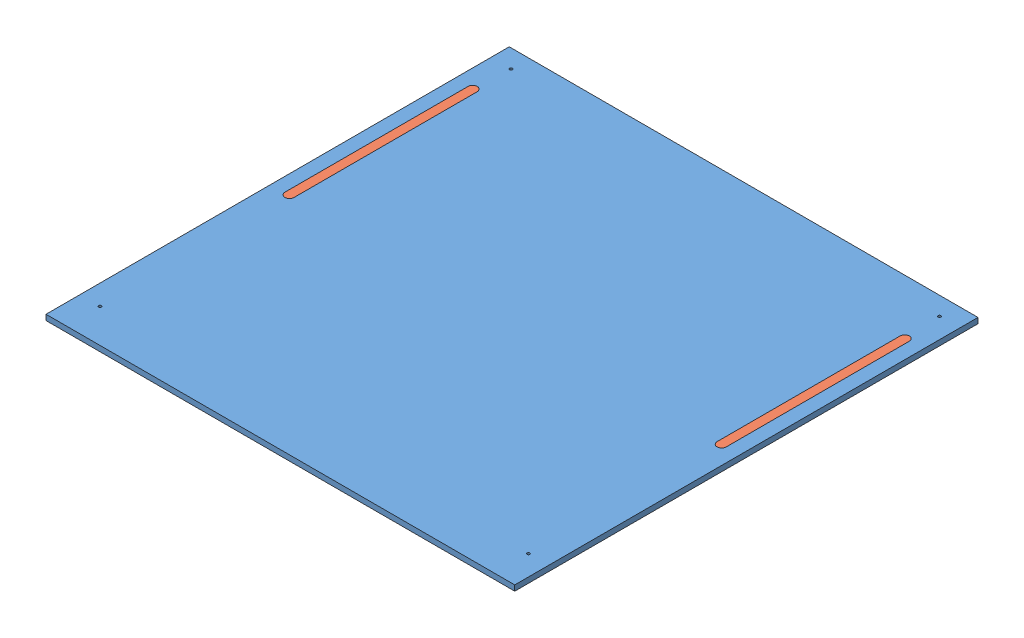
SolidWorks assembly top_board_light_stripe_assem, configuration Default. Lengths in mm.
Overall size (512 6 506).
3 component instances, 2 part files, 5 mates.
Components (placement in the parent):
- top_board_light_stripe-1: top_board_light_stripe [Default] at (107.7343 336.6542 389.8099) size (512 6 506)
- light_reflector-1: light_reflector [Default] at (121.7343 342.6542 449.8099) x (0 0 1) z (1 0 0) size (210 6 10)
- light_reflector-3: light_reflector [Default] at (593.7343 342.6542 449.8099) x (0 0 1) z (1 0 0) size (210 6 10)
Mates (geometry in assembly coordinates):
- Concentric1: concentric anti-aligned: cylinder of top_board_light_stripe-1 through (121.7343 342.6542 449.8099) axis (0 -1 0) radius 5; cylinder of light_reflector-1 through (121.7343 336.6542 449.8099) axis (0 1 0) radius 5
- Concentric2: concentric aligned: cylinder of top_board_light_stripe-1 through (121.7343 342.6542 649.8099) axis (0 -1 0) radius 5; circle of light_reflector-1
- Coincident2: coincident anti-aligned: line of top_board_light_stripe-1 through (116.7343 342.6542 449.8099) axis (0 0 1); line of light_reflector-1 through (116.7343 342.6542 649.8099) axis (0 0 -1)
- Concentric3: concentric: cylinder of top_board_light_stripe-1 through (593.7343 342.6542 649.8099) axis (0 -1 0) radius 5; cylinder of light_reflector-3 through (593.7343 336.6542 649.8099) axis (0 1 0) radius 5
- Coincident3: coincident anti-aligned: circle of top_board_light_stripe-1; circle of light_reflector-3
